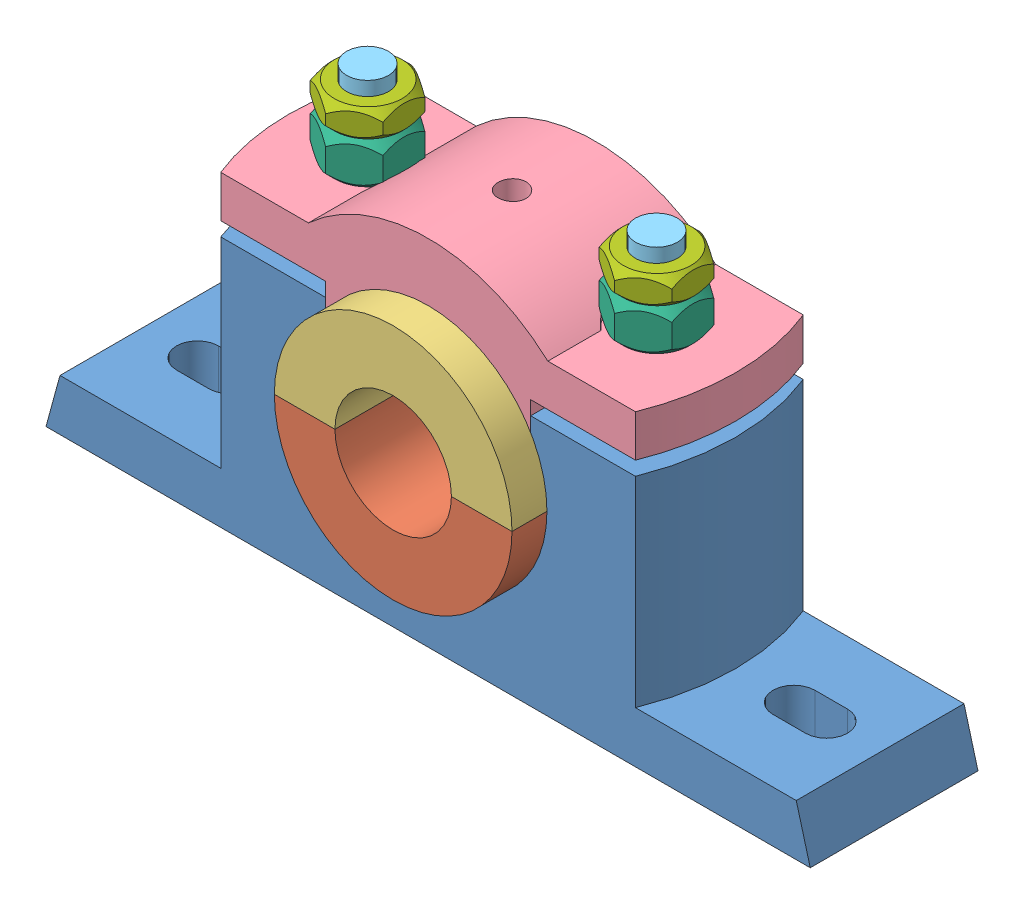
SolidWorks assembly Assem2, configuration Default. Lengths in mm.
Overall size (164 84 51).
10 component instances, 7 part files, 13 mates.
Components (placement in the parent):
- CASTING-1: CASTING [Default] at (88.3673 42.3971 122.5544) size (164 54 36)
- brass2-1: brass2 [Default] at (88.3673 80.3971 148.0544) x (1 0 0) z (0 1 0) size (51 51 25.5)
- brash1-1: brash1 [Default] at (88.3673 80.3971 97.0544) x (0 1 0) z (1 0 0) size (25.5 51 51)
- cap2-1: cap2 [Default] at (88.3673 80.3971 122.5544) size (96 32 36)
- bolt-1: bolt [Default] at (57.3673 47.3971 122.5544) x (1 0 0) z (0 1 0) size (19 19 82)
- nut-1: nut [Default] at (57.3673 112.8971 122.5544) x (1 0 0) z (0 1 0) size (15.59 19.8 9)
- nut2-1: nut2 [Default] at (57.3673 120.3971 122.5544) x (1 0 0) z (0 1 0) size (15.59 19.85 6)
- nut2-2: nut2 [Default] at (119.3673 120.3971 122.5544) x (-1 0 0) z (0 -1 0) size (15.59 19.85 6)
- bolt-2: bolt [Default] at (119.3673 47.3971 122.5544) x (1 0 0) z (0 1 0) size (19 19 82)
- nut-2: nut [Default] at (119.3673 112.8971 122.5544) x (-1 0 0) z (0 -1 0) size (15.59 19.8 9)
Mates (geometry in assembly coordinates):
- Concentric9: concentric anti-aligned: cylinder of CASTING-1 through (88.3673 80.3971 140.5544) axis (0 0 -1) radius 19; cylinder of brass2-1 through (88.3673 80.3971 148.0544) axis (0 0 1) radius 17.5
- Concentric10: concentric anti-aligned: cylinder of CASTING-1 through (88.3673 61.3971 122.5544) axis (0 1 0) radius 3; cylinder of brass2-1 through (88.3673 66.8971 122.5544) axis (0 -1 0) radius 3
- Concentric11: concentric anti-aligned: cylinder of brass2-1 through (88.3673 80.3971 148.0544) axis (0 0 -1) radius 12.5; cylinder of brash1-1 through (88.3673 80.3971 97.0544) axis (0 0 1) radius 12.5
- Coincident17: coincident: plane of brass2-1 through (88.3673 80.3971 148.0544) normal (0 1 0); line of brash1-1 through (62.8673 80.3971 148.0544) axis (1 0 0)
- Coincident18: coincident aligned: plane of brass2-1 through (62.8673 80.3971 97.0544) normal (0 0 -1); plane of brash1-1 through (88.3673 80.3971 97.0544) normal (0 0 -1)
- Concentric12: concentric aligned: cylinder of brash1-1 through (88.3673 80.3971 97.0544) axis (0 0 -1) radius 17.5; cylinder of cap2-1 through (88.3673 80.3971 140.5544) axis (0 0 -1) radius 19
- Concentric13: concentric aligned: cylinder of CASTING-1 through (57.3673 96.3971 122.5544) axis (0 1 0) radius 4.5; cylinder of cap2-1 through (57.3673 108.3971 122.5544) axis (0 1 0) radius 4.5
- Coincident19: coincident anti-aligned: plane of CASTING-1 through (88.3673 50.3971 122.5544) normal (0 -1 0); plane of bolt-1 through (57.3673 50.3971 122.5544) normal (0 1 0)
- Coincident21: coincident anti-aligned: circle of cap2-1; cylinder of bolt-1 through (57.3673 126.3971 122.5544) axis (0 -1 0) radius 4.5
- Coincident22: coincident anti-aligned: cylinder of bolt-1 through (57.3673 126.3971 122.5544) axis (0 -1 0) radius 4.5; circle of nut-1
- Coincident23: coincident anti-aligned: plane of cap2-1 through (38.3673 108.3971 140.5544) normal (0 1 0); circle of nut-1
- Coincident26: coincident anti-aligned: plane of nut-1 through (57.3673 117.3971 122.5544) normal (0 1 0); plane of nut2-1 through (57.3673 117.3971 122.5544) normal (0 -1 0)
- Coincident27: coincident anti-aligned: cylinder of bolt-1 through (57.3673 126.3971 122.5544) axis (0 -1 0) radius 4.5; circle of nut2-1
